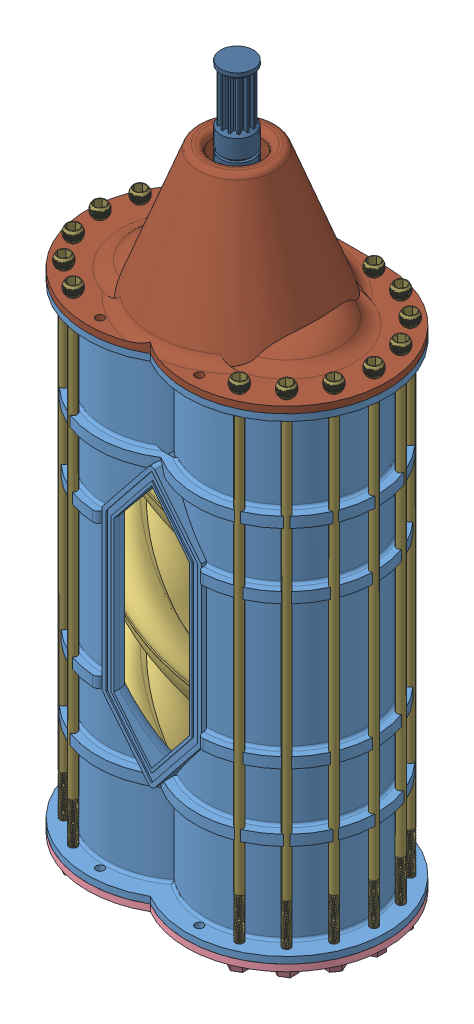
SolidWorks assembly supercharger, configuration Default. Lengths in mm.
Overall size (226 539.76 151).
43 component instances, 13 part files, 108 mates.
Components (placement in the parent):
- casing-1: casing [Default] at (105.1186 33.7762 242.5866) size (226 360 151)
- cork screw one-1: cork screw one [Default] at (180.1186 333.7762 242.5866) x (0.113215 0 0.993571) z (-0.993571 0 0.113215) size (101.97 371 100.73)
- cork screw two-1: cork screw two [Default] at (105.1186 33.7762 242.5866) x (-0.675443 0 -0.737412) z (0.737412 0 -0.675443) size (99.6 341 99.85)
- LidOne-1: LidOne [Default] at (180.1186 28.7762 242.5866) x (-1 0 0) z (0 0 1) size (226 23.47 151)
- heligearAntiClockwise-1: heligearAntiClockwise [Default] at (180.1186 339.7762 242.5866) x (-0.760972 0 0.648785) z (-0.648785 0 -0.760972) size (76.65 15 76.65)
- heligearClockwise-1: heligearClockwise [Default] at (105.1186 339.7762 242.5866) x (-0.120243 0 0.992744) z (-0.992744 0 -0.120243) size (76.65 15 76.65)
- axle support-2: axle support [Default] at (126.5104 354.7762 251.6132) size (28.48 5 80.98)
- heligearAntiClockwise 38mm-1: heligearAntiClockwise 38mm [Default] at (180.1186 359.7762 242.5866) x (0.451037 0 0.892505) z (-0.892505 0 0.451037) size (40.05 20 40.06)
- heligearClockwise 38mm-1: heligearClockwise 38mm [Default] at (142.6186 359.7762 242.5885) x (0.774286 0 0.632836) z (-0.632836 0 0.774286) size (40.05 15 40.06)
- PTaxle-1: PTaxle [Default] at (142.6186 357.7762 242.5885) x (0.987746 0 -0.156068) z (0.156068 0 0.987746) size (25 190.76 25)
- LidGearSide-1: LidGearSide [Default] at (105.1186 388.7762 242.5866) size (226 108.1 151)
- long bolts-20: long bolts [Default] at (79.8615 14.7762 303.5627) x (0 1 0) z (0 0 1) size (388.15 12.67 12.66)
- long bolts-21: long bolts [Default] at (226.7877 14.7762 195.9176) x (0 1 0) z (0 0 1) size (388.15 12.67 12.66)
- long bolts-22: long bolts [Default] at (205.3757 14.7762 181.6106) x (0 1 0) z (0 0 1) size (388.15 12.67 12.66)
- long bolts-23: long bolts [Default] at (180.1186 14.7762 176.5866) x (0 1 0) z (0 0 1) size (388.15 12.67 12.66)
- long bolts-24: long bolts [Default] at (105.1186 14.7762 176.5866) x (0 1 0) z (0 0 1) size (388.15 12.67 12.66)
- long bolts-25: long bolts [Default] at (79.8615 14.7762 181.6106) x (0 1 0) z (0 0 1) size (388.15 12.67 12.66)
- long bolts-26: long bolts [Default] at (58.4496 14.7762 195.9176) x (0 1 0) z (0 0 1) size (388.15 12.67 12.66)
- long bolts-27: long bolts [Default] at (44.1426 14.7762 217.3295) x (0 1 0) z (0 0 1) size (388.15 12.67 12.66)
- long bolts-28: long bolts [Default] at (39.1186 14.7762 242.5866) x (0 1 0) z (0 0 1) size (388.15 12.67 12.66)
- long bolts-29: long bolts [Default] at (44.1426 14.7762 267.8437) x (0 1 0) z (0 0 1) size (388.15 12.67 12.66)
- long bolts-30: long bolts [Default] at (58.4496 14.7762 289.2557) x (0 1 0) z (0 0 1) size (388.15 12.67 12.66)
- long bolts-32: long bolts [Default] at (241.0947 14.7762 217.3295) x (0 1 0) z (0.991179 0 -0.132529) size (388.15 12.67 12.66)
- long bolts-33: long bolts [Default] at (246.1186 14.7762 242.5866) x (0 1 0) z (0.903937 0 0.427666) size (388.15 12.67 12.66)
- long bolts-34: long bolts [Default] at (241.0947 14.7762 267.8437) x (0 1 0) z (-0.949196 0 -0.314684) size (388.15 12.67 12.66)
- long bolts-35: long bolts [Default] at (226.7877 14.7762 289.2557) x (0 1 0) z (-0.597909 0 0.801564) size (388.15 12.67 12.66)
- long bolts-36: long bolts [Default] at (205.3757 14.7762 303.5627) x (0 1 0) z (-0.95126 0 -0.308391) size (388.15 12.67 12.66)
- Nut 6mm-17: Nut 6mm [Default] at (205.3757 17.7762 303.5627) size (12 6 13.86)
- Nut 6mm-18: Nut 6mm [Default] at (226.7877 17.7762 289.2557) size (12 6 13.86)
- Nut 6mm-20: Nut 6mm [Default] at (241.0947 17.7762 217.3295) size (12 6 13.86)
- Nut 6mm-21: Nut 6mm [Default] at (226.7877 17.7762 195.9176) size (12 6 13.86)
- Nut 6mm-22: Nut 6mm [Default] at (241.0947 17.7762 267.8437) x (0.907106 0 -0.420902) z (0.420902 0 0.907106) size (12 6 13.86)
- Nut 6mm-23: Nut 6mm [Default] at (246.1186 17.7762 242.5866) size (12 6 13.86)
- Nut 6mm-24: Nut 6mm [Default] at (205.3757 17.7762 181.6106) size (12 6 13.86)
- Nut 6mm-25: Nut 6mm [Default] at (105.1186 17.7762 176.5866) size (12 6 13.86)
- Nut 6mm-26: Nut 6mm [Default] at (180.1186 17.7762 176.5866) size (12 6 13.86)
- Nut 6mm-27: Nut 6mm [Default] at (79.8615 17.7762 303.5627) size (12 6 13.86)
- Nut 6mm-29: Nut 6mm [Default] at (44.1426 17.7762 217.3295) size (12 6 13.86)
- Nut 6mm-30: Nut 6mm [Default] at (79.8615 17.7762 181.6106) size (12 6 13.86)
- Nut 6mm-31: Nut 6mm [Default] at (58.4496 17.7762 195.9176) size (12 6 13.86)
- Nut 6mm-32: Nut 6mm [Default] at (44.1426 17.7762 267.8437) size (12 6 13.86)
- Nut 6mm-33: Nut 6mm [Default] at (39.1186 17.7762 242.5866) size (12 6 13.86)
- Nut 6mm-34: Nut 6mm [Default] at (58.4496 17.7762 289.2557) size (12 6 13.86)
Mates (geometry in assembly coordinates):
- Coincident1: coincident: plane of ? through (180.1186 363.7762 242.5866) normal (0 1 0); plane of cork screw one-1 through (180.1186 384.7762 242.5866) normal (0 1 0)
- Concentric1: concentric: cylinder of ? through (180.1186 348.7762 242.5866) axis (0 1 0) radius 5; cylinder of cork screw one-1 through (180.1186 384.7762 242.5866) axis (0 -1 0) radius 5
- Concentric2: concentric: cylinder of ? through (105.1186 348.7762 242.5866) axis (0 1 0) radius 5; cylinder of cork screw two-1 through (105.1186 354.7762 242.5866) axis (0 -1 0) radius 5
- Coincident2: coincident: plane of ? through (105.1186 363.7762 242.5866) normal (0 1 0); plane of cork screw two-1 through (105.1186 354.7762 242.5866) normal (0 1 0)
- Coincident3: coincident: plane of ? through (180.1186 363.7762 242.5866) normal (0 1 0); plane of ? through (105.1186 363.7762 242.5866) normal (0 1 0)
- Concentric3: concentric anti-aligned: cylinder of casing-1 through (105.1186 383.7762 242.5866) axis (0 -1 0) radius 50.5; circle of ?
- Coincident5: coincident anti-aligned: plane of casing-1 through (180.1186 28.7762 242.5866) normal (0 -1 0); plane of LidOne-1 through (180.1186 28.7762 242.5866) normal (0 1 0)
- Concentric6: concentric anti-aligned: cylinder of casing-1 through (180.1186 38.7762 308.5866) axis (0 -1 0) radius 3; cylinder of LidOne-1 through (180.1186 23.7762 308.5866) axis (0 1 0) radius 3
- Concentric7: concentric anti-aligned: cylinder of casing-1 through (105.1186 38.7762 308.5866) axis (0 -1 0) radius 3; cylinder of LidOne-1 through (105.1186 23.7762 308.5866) axis (0 1 0) radius 3
- Coincident11: coincident: circle of LidGearSide-1; cylinder of ? through (180.1186 393.7762 308.5866) axis (0 -1 0) radius 3
- Coincident20: coincident: circle of LidGearSide-1; plane of ? through (180.1186 393.7762 308.5866) normal (0 -1 0)
- Concentric39: concentric anti-aligned: cylinder of cork screw one-1 through (180.1186 384.7762 242.5866) axis (0 -1 0) radius 5; cylinder of ? through (180.1186 339.7762 242.5866) axis (0 1 0) radius 5
- Distance1: distance = 9 mm aligned: plane of cork screw one-1 through (180.1186 384.7762 242.5866) normal (0 1 0); plane of ? through (180.1186 354.7762 242.5866) normal (0 1 0)
- Concentric40: concentric anti-aligned: cylinder of cork screw two-1 through (105.1186 354.7762 242.5866) axis (0 -1 0) radius 5; cylinder of ? through (105.2219 339.1634 240.0324) axis (0 1 0) radius 5
- Distance2: distance = 9 mm aligned: plane of cork screw two-1 through (105.1186 354.7762 242.5866) normal (0 1 0); plane of ? through (105.2219 354.1634 240.0324) normal (0 1 0)
- Concentric41: concentric aligned: cylinder of casing-1 through (105.1186 354.7762 242.5866) axis (0 -1 0) radius 5; cylinder of cork screw two-1 through (105.1186 354.7762 242.5866) axis (0 -1 0) radius 5
- Concentric42: concentric anti-aligned: cylinder of cork screw one-1 through (180.1186 384.7762 242.5866) axis (0 -1 0) radius 5; cylinder of heligearAntiClockwise-1 through (180.1186 339.7762 242.5866) axis (0 1 0) radius 4.5
- Concentric43: concentric anti-aligned: cylinder of cork screw two-1 through (105.1186 354.7762 242.5866) axis (0 -1 0) radius 5; cylinder of heligearClockwise-1 through (105.1186 339.7762 242.5866) axis (0 1 0) radius 4.5
- Distance4: distance = 1 mm anti-aligned: plane of casing-1 through (105.1186 338.7762 242.5866) normal (0 1 0); plane of heligearClockwise-1 through (105.1186 339.7762 242.5866) normal (0 -1 0)
- Parallel3: parallel aligned: plane of cork screw two-1 through (105.1186 354.7762 242.5866) normal (0 1 0); plane of heligearClockwise-1 through (105.1186 354.7762 242.5866) normal (0 1 0)
- Coincident55: coincident aligned: plane of cork screw two-1 through (105.1186 354.7762 242.5866) normal (0 1 0); plane of heligearClockwise-1 through (105.1186 354.7762 242.5866) normal (0 1 0)
- Concentric46: concentric aligned: circle of casing-1; cylinder of cork screw one-1 through (180.1186 384.7762 242.5866) axis (0 -1 0) radius 5
- Concentric47: concentric aligned: circle of casing-1; cylinder of cork screw two-1 through (105.1186 354.7762 242.5866) axis (0 -1 0) radius 5
- Distance5: distance = 6 mm anti-aligned: plane of cork screw one-1 through (169.674 333.7762 291.4835) normal (0 1 0); plane of heligearAntiClockwise-1 through (180.1186 339.7762 242.5866) normal (0 -1 0)
- Lock1: lock: unknown of cork screw two-1; unknown of heligearClockwise-1
- Coincident80: coincident: point of cork screw two-1; point of heligearClockwise-1
- Coincident81: coincident: line of cork screw one-1 through (177.4846 344.7762 246.2352) axis (0 1 0); point of heligearAntiClockwise-1
- Coincident83: coincident aligned: plane of heligearAntiClockwise-1 through (180.1186 354.7762 242.5866) normal (0 1 0); plane of heligearClockwise-1 through (105.1186 354.7762 242.5866) normal (0 1 0)
- GearMate7: gear = 76.5 : 76.5 mm: cylinder of heligearAntiClockwise-1 through (180.1186 354.7762 242.5866) axis (0 -1 0) radius 38.25; cylinder of heligearClockwise-1 through (105.1186 354.7762 242.5866) axis (0 -1 0) radius 38.25
- Coincident85: coincident aligned: plane of casing-1 through (105.1186 354.7762 242.5866) normal (0 1 0); circle of axle support-2
- Concentric49: concentric aligned: circle of cork screw one-1; cylinder of heligearAntiClockwise 38mm-1 through (180.1186 359.7762 242.5866) axis (0 1 0) radius 4.5
- Coincident90: coincident: line of cork screw one-1 through (179.715 344.7762 237.6029) axis (0 1 0); point of heligearAntiClockwise 38mm-1
- Tangent1: tangent: curve of casing-1; cylinder of axle support-2 through (137.6186 356.7762 212.5866) axis (0 -1 0) radius 2.5
- Concentric52: concentric anti-aligned: cylinder of casing-1 through (137.6186 344.7762 272.5866) axis (0 1 0) radius 2.5; cylinder of axle support-2 through (137.6186 358.7762 272.5866) axis (0 -1 0) radius 2.5
- Coincident92: coincident aligned: plane of heligearAntiClockwise 38mm-1 through (180.1186 374.7762 242.5866) normal (0 1 0); plane of heligearClockwise 38mm-1 through (142.6186 374.7762 242.5885) normal (0 1 0)
- Coincident93: coincident aligned: plane of axle support-2 through (142.6186 359.7762 242.5885) normal (0 1 0); circle of heligearClockwise 38mm-1
- GearMate9: gear = 40 : 40 mm: cylinder of heligearClockwise 38mm-1 through (142.6186 374.7762 242.5885) axis (0 -1 0) radius 20; cylinder of heligearAntiClockwise 38mm-1 through (180.1186 374.7762 242.5866) axis (0 -1 0) radius 20
- Concentric54: concentric anti-aligned: cylinder of heligearClockwise 38mm-1 through (142.6186 359.7762 242.5885) axis (0 1 0) radius 4.5; cylinder of PTaxle-1 through (142.6186 357.7762 242.5885) axis (0 -1 0) radius 12.5
- Lock8: lock: unknown of heligearClockwise 38mm-1; unknown of PTaxle-1
- Coincident94: coincident anti-aligned: plane of casing-1 through (105.1186 388.7762 242.5866) normal (0 1 0); plane of LidGearSide-1 through (105.1186 388.7762 242.5866) normal (0 -1 0)
- Concentric55: concentric aligned: cylinder of casing-1 through (241.0947 388.7762 217.3295) axis (0 -1 0) radius 3; cylinder of LidGearSide-1 through (241.0947 393.7762 217.3295) axis (0 -1 0) radius 3
- Concentric56: concentric aligned: cylinder of casing-1 through (241.0947 388.7762 267.8437) axis (0 -1 0) radius 3; cylinder of LidGearSide-1 through (241.0947 393.7762 267.8437) axis (0 -1 0) radius 3
- Concentric57: concentric anti-aligned: circle of axle support-2; cylinder of PTaxle-1 through (142.6186 357.7762 242.5885) axis (0 -1 0) radius 12.5
- Concentric58: concentric anti-aligned: circle of casing-1; circle of axle support-2
- Concentric60: concentric aligned: cylinder of LidGearSide-1 through (79.8615 393.7762 303.5627) axis (0 -1 0) radius 3; cylinder of long bolts-20 through (79.8615 394.7762 303.5627) axis (0 -1 0) radius 3
- Concentric61: concentric aligned: cylinder of LidGearSide-1 through (58.4496 393.7762 289.2557) axis (0 -1 0) radius 3; cylinder of long bolts-30 through (58.4496 394.7762 289.2557) axis (0 -1 0) radius 3
- Concentric62: concentric aligned: cylinder of LidGearSide-1 through (44.1426 393.7762 267.8437) axis (0 -1 0) radius 3; cylinder of long bolts-29 through (44.1426 394.7762 267.8437) axis (0 -1 0) radius 3
- Concentric63: concentric aligned: cylinder of LidGearSide-1 through (39.1186 393.7762 242.5866) axis (0 -1 0) radius 3; cylinder of long bolts-28 through (39.1186 394.7762 242.5866) axis (0 -1 0) radius 3
- Concentric64: concentric aligned: cylinder of LidGearSide-1 through (44.1426 393.7762 217.3295) axis (0 -1 0) radius 3; cylinder of long bolts-27 through (44.1426 394.7762 217.3295) axis (0 -1 0) radius 3
- Concentric65: concentric aligned: cylinder of LidGearSide-1 through (58.4496 393.7762 195.9176) axis (0 -1 0) radius 3; cylinder of long bolts-26 through (58.4496 394.7762 195.9176) axis (0 -1 0) radius 3
- Concentric66: concentric aligned: cylinder of LidGearSide-1 through (79.8615 393.7762 181.6106) axis (0 -1 0) radius 3; cylinder of long bolts-25 through (79.8615 394.7762 181.6106) axis (0 -1 0) radius 3
- Concentric67: concentric aligned: cylinder of LidGearSide-1 through (105.1186 393.7762 176.5866) axis (0 -1 0) radius 3; cylinder of long bolts-24 through (105.1186 394.7762 176.5866) axis (0 -1 0) radius 3
- Concentric68: concentric aligned: cylinder of LidGearSide-1 through (180.1186 393.7762 176.5866) axis (0 -1 0) radius 3; cylinder of long bolts-23 through (180.1186 394.7762 176.5866) axis (0 -1 0) radius 3
- Concentric69: concentric aligned: cylinder of LidGearSide-1 through (205.3757 393.7762 181.6106) axis (0 -1 0) radius 3; cylinder of long bolts-22 through (205.3757 394.7762 181.6106) axis (0 -1 0) radius 3
- Concentric70: concentric aligned: cylinder of LidGearSide-1 through (226.7877 393.7762 195.9176) axis (0 -1 0) radius 3; cylinder of long bolts-21 through (226.7877 394.7762 195.9176) axis (0 -1 0) radius 3
- Concentric71: concentric aligned: cylinder of LidGearSide-1 through (241.0947 393.7762 217.3295) axis (0 -1 0) radius 3; cylinder of long bolts-32 through (241.0947 394.7762 217.3295) axis (0 -1 0) radius 3
- Concentric73: concentric aligned: cylinder of LidGearSide-1 through (246.1186 393.7762 242.5866) axis (0 -1 0) radius 3; cylinder of long bolts-33 through (246.1186 394.7762 242.5866) axis (0 -1 0) radius 3
- Concentric74: concentric aligned: cylinder of LidGearSide-1 through (241.0947 393.7762 267.8437) axis (0 -1 0) radius 3; cylinder of long bolts-34 through (241.0947 394.7762 267.8437) axis (0 -1 0) radius 3
- Concentric75: concentric aligned: cylinder of LidGearSide-1 through (226.7877 393.7762 289.2557) axis (0 -1 0) radius 3; cylinder of long bolts-35 through (226.7877 394.7762 289.2557) axis (0 -1 0) radius 3
- Concentric76: concentric aligned: cylinder of LidGearSide-1 through (205.3757 393.7762 303.5627) axis (0 -1 0) radius 3; cylinder of long bolts-36 through (205.3757 394.7762 303.5627) axis (0 -1 0) radius 3
- Coincident96: coincident anti-aligned: plane of LidGearSide-1 through (105.1186 393.7762 242.5866) normal (0 1 0); circle of long bolts-20
- Coincident97: coincident anti-aligned: plane of LidGearSide-1 through (105.1186 393.7762 242.5866) normal (0 1 0); circle of long bolts-30
- Coincident98: coincident anti-aligned: plane of LidGearSide-1 through (105.1186 393.7762 242.5866) normal (0 1 0); circle of long bolts-29
- Coincident99: coincident anti-aligned: plane of LidGearSide-1 through (105.1186 393.7762 242.5866) normal (0 1 0); circle of long bolts-28
- Coincident100: coincident anti-aligned: plane of LidGearSide-1 through (105.1186 393.7762 242.5866) normal (0 1 0); circle of long bolts-27
- Coincident101: coincident anti-aligned: plane of LidGearSide-1 through (105.1186 393.7762 242.5866) normal (0 1 0); circle of long bolts-26
- Coincident103: coincident anti-aligned: plane of LidGearSide-1 through (105.1186 393.7762 242.5866) normal (0 1 0); circle of long bolts-24
- Coincident104: coincident anti-aligned: plane of LidGearSide-1 through (105.1186 393.7762 242.5866) normal (0 1 0); circle of long bolts-23
- Coincident105: coincident anti-aligned: plane of LidGearSide-1 through (105.1186 393.7762 242.5866) normal (0 1 0); circle of long bolts-22
- Coincident106: coincident anti-aligned: plane of LidGearSide-1 through (105.1186 393.7762 242.5866) normal (0 1 0); circle of long bolts-21
- Coincident107: coincident anti-aligned: plane of LidGearSide-1 through (105.1186 393.7762 242.5866) normal (0 1 0); circle of long bolts-32
- Coincident108: coincident anti-aligned: plane of LidGearSide-1 through (105.1186 393.7762 242.5866) normal (0 1 0); plane of long bolts-33 through (246.1186 393.7762 242.5866) normal (0 -1 0)
- Coincident109: coincident anti-aligned: plane of LidGearSide-1 through (105.1186 393.7762 242.5866) normal (0 1 0); circle of long bolts-34
- Concentric78: concentric anti-aligned: cylinder of long bolts-20 through (79.8615 394.7762 303.5627) axis (0 -1 0) radius 3; cylinder of Nut 6mm-27 through (79.8615 17.7762 303.5627) axis (0 1 0) radius 3
- Concentric79: concentric anti-aligned: cylinder of long bolts-30 through (58.4496 394.7762 289.2557) axis (0 -1 0) radius 3; cylinder of Nut 6mm-34 through (58.4496 17.7762 289.2557) axis (0 1 0) radius 3
- Concentric80: concentric anti-aligned: cylinder of long bolts-29 through (44.1426 394.7762 267.8437) axis (0 -1 0) radius 3; cylinder of Nut 6mm-32 through (44.1426 17.7762 267.8437) axis (0 1 0) radius 3
- Concentric81: concentric aligned: cylinder of long bolts-28 through (39.1186 394.7762 242.5866) axis (0 -1 0) radius 3; circle of Nut 6mm-33
- Concentric82: concentric anti-aligned: cylinder of long bolts-27 through (44.1426 394.7762 217.3295) axis (0 -1 0) radius 3; cylinder of Nut 6mm-29 through (44.1426 17.7762 217.3295) axis (0 1 0) radius 3
- Concentric83: concentric anti-aligned: cylinder of long bolts-26 through (58.4496 394.7762 195.9176) axis (0 -1 0) radius 3; cylinder of Nut 6mm-31 through (58.4496 17.7762 195.9176) axis (0 1 0) radius 3
- Concentric84: concentric anti-aligned: cylinder of long bolts-25 through (79.8615 394.7762 181.6106) axis (0 -1 0) radius 3; cylinder of Nut 6mm-30 through (79.8615 17.7762 181.6106) axis (0 1 0) radius 3
- Concentric85: concentric anti-aligned: cylinder of long bolts-24 through (105.1186 394.7762 176.5866) axis (0 -1 0) radius 3; cylinder of Nut 6mm-25 through (105.1186 17.7762 176.5866) axis (0 1 0) radius 3
- Coincident112: coincident: plane of LidOne-1 through (180.1186 23.7762 242.5866) normal (0 -1 0); line of Nut 6mm-27 through (73.8615 23.7762 300.0986) axis (0 0 1)
- Coincident113: coincident: plane of LidOne-1 through (180.1186 23.7762 242.5866) normal (0 -1 0); line of Nut 6mm-34 through (52.4496 23.7762 292.7198) axis (0.866025 0 0.5)
- Coincident114: coincident: plane of LidOne-1 through (180.1186 23.7762 242.5866) normal (0 -1 0); line of Nut 6mm-32 through (38.1426 23.7762 271.3078) axis (0.866025 0 0.5)
- Coincident115: coincident: plane of LidOne-1 through (180.1186 23.7762 242.5866) normal (0 -1 0); line of Nut 6mm-33 through (33.1186 23.7762 246.0507) axis (0.866025 0 0.5)
- Coincident116: coincident: plane of LidOne-1 through (180.1186 23.7762 242.5866) normal (0 -1 0); line of Nut 6mm-29 through (38.1426 23.7762 220.7936) axis (0.866025 0 0.5)
- Coincident117: coincident: plane of LidOne-1 through (180.1186 23.7762 242.5866) normal (0 -1 0); line of Nut 6mm-31 through (52.4496 23.7762 199.3817) axis (0.866025 0 0.5)
- Coincident118: coincident: plane of LidOne-1 through (180.1186 23.7762 242.5866) normal (0 -1 0); line of Nut 6mm-30 through (73.8615 23.7762 185.0747) axis (0.866025 0 0.5)
- Coincident119: coincident: plane of LidOne-1 through (180.1186 23.7762 242.5866) normal (0 -1 0); moEndPointRef_w of Nut 6mm-25
- Concentric86: concentric aligned: cylinder of long bolts-36 through (205.3757 394.7762 303.5627) axis (0 -1 0) radius 3; circle of Nut 6mm-17
- Concentric87: concentric aligned: cylinder of long bolts-35 through (226.7877 394.7762 289.2557) axis (0 -1 0) radius 3; circle of Nut 6mm-18
- Concentric88: concentric aligned: cylinder of long bolts-34 through (241.0947 394.7762 267.8437) axis (0 -1 0) radius 3; circle of Nut 6mm-22
- Concentric90: concentric aligned: cylinder of long bolts-33 through (246.1186 394.7762 242.5866) axis (0 -1 0) radius 3; circle of Nut 6mm-23
- Concentric92: concentric aligned: cylinder of long bolts-32 through (241.0947 394.7762 217.3295) axis (0 -1 0) radius 3; circle of Nut 6mm-20
- Concentric93: concentric aligned: cylinder of long bolts-21 through (226.7877 394.7762 195.9176) axis (0 -1 0) radius 3; circle of Nut 6mm-21
- Concentric94: concentric anti-aligned: cylinder of long bolts-22 through (205.3757 394.7762 181.6106) axis (0 -1 0) radius 3; circle of Nut 6mm-24
- Concentric95: concentric aligned: cylinder of long bolts-23 through (180.1186 394.7762 176.5866) axis (0 -1 0) radius 3; circle of Nut 6mm-26
- Coincident120: coincident: plane of LidOne-1 through (180.1186 23.7762 242.5866) normal (0 -1 0); line of Nut 6mm-21 through (232.7877 23.7762 199.3817) axis (0 0 -1)
- Coincident121: coincident: plane of LidOne-1 through (180.1186 23.7762 242.5866) normal (0 -1 0); line of Nut 6mm-24 through (211.3757 23.7762 185.0747) axis (0 0 -1)
- Coincident122: coincident: plane of LidOne-1 through (180.1186 23.7762 242.5866) normal (0 -1 0); line of Nut 6mm-26 through (186.1186 23.7762 180.0507) axis (0 0 -1)
- Coincident123: coincident: plane of LidOne-1 through (180.1186 23.7762 242.5866) normal (0 -1 0); line of Nut 6mm-20 through (247.0947 23.7762 220.7936) axis (0 0 -1)
- Coincident124: coincident: plane of LidOne-1 through (180.1186 23.7762 242.5866) normal (0 -1 0); line of Nut 6mm-23 through (252.1186 23.7762 246.0507) axis (0 0 -1)
- Coincident125: coincident: plane of LidOne-1 through (180.1186 23.7762 242.5866) normal (0 -1 0); line of Nut 6mm-22 through (245.0793 23.7762 262.176) axis (-0.996028 0 -0.089042)
- Coincident126: coincident: plane of LidOne-1 through (180.1186 23.7762 242.5866) normal (0 -1 0); line of Nut 6mm-18 through (232.7877 23.7762 285.7916) axis (-0.866025 0 -0.5)
- Coincident127: coincident: plane of LidOne-1 through (180.1186 23.7762 242.5866) normal (0 -1 0); line of Nut 6mm-17 through (211.3757 23.7762 300.0986) axis (-0.866025 0 -0.5)
- Coincident128: coincident anti-aligned: plane of LidGearSide-1 through (105.1186 393.7762 242.5866) normal (0 1 0); circle of long bolts-36
- Coincident129: coincident anti-aligned: plane of LidGearSide-1 through (105.1186 393.7762 242.5866) normal (0 1 0); circle of long bolts-35
- Coincident130: coincident anti-aligned: plane of LidGearSide-1 through (105.1186 393.7762 242.5866) normal (0 1 0); circle of long bolts-25
